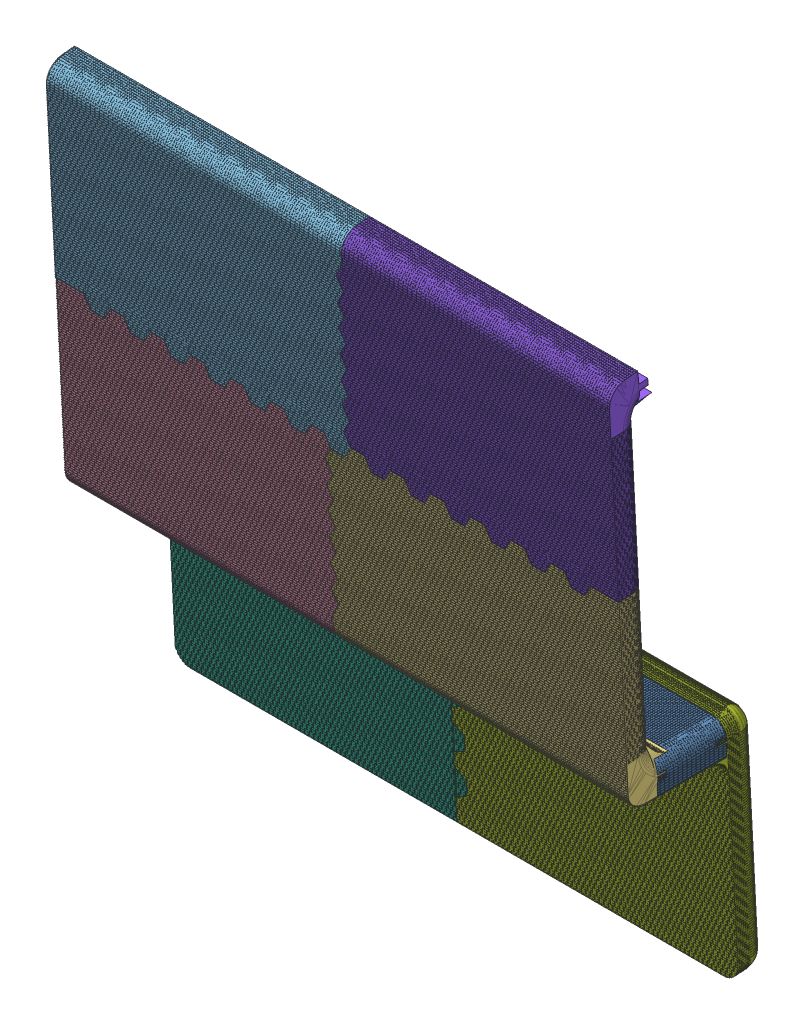
SolidWorks assembly A_B_C_subSplitParts, configuration Default. Lengths in mm.
Overall size (453.06 467.07 127.69).
8 component instances, 8 part files, 14 mates.
Components (placement in the parent):
- B_neo_texture_complete_55mm_1of2-1: B_neo_texture_complete_55mm_1of2 [Default] at (-24.2238 128.3057 314.216) x (1 0 0) z (0 1 0) size (219.85 54.89 24)
- B_neo_texture_complete_55mm_2of2-1: B_neo_texture_complete_55mm_2of2 [Default] at (-24.2238 128.3057 314.216) x (1 0 0) z (0 1 0) size (236.08 54.89 24)
- C_assy_half_hexCut_1of4-1: C_assy_half_hexCut_1of4 [Default] at (189.9657 195.3033 328.4127) x (0 0.99863 0.052336) z (1 0 0) size (151.85 36.3 237.2)
- C_assy_half_hexCut_2of4-1: C_assy_half_hexCut_2of4 [Default] at (189.9657 195.3033 328.4127) x (0 0.99863 0.052336) z (1 0 0) size (151.85 37.29 220.92)
- C_assy_half_hexCut_3of4_Completed-1: C_assy_half_hexCut_3of4_Completed [Default] at (35.1569 242.0747 353.6128) x (0 -0.99863 -0.052336) z (-1 0 0) size (161.09 36.3 237.2)
- A_neo_part1-1: A_neo_part1 [Default] at (190.2996 258.8119 374.6631) x (0 0.99863 0.052336) z (0 0.052336 -0.99863) size (187.3 234.72 36.32)
- A_neo_part2-1: A_neo_part2 [Default] at (190.2996 258.8119 374.6631) x (0 0.99863 0.052336) z (0 0.052336 -0.99863) size (187.33 225.47 36.32)
- C_assy_half_hexCut_4of4-1: C_assy_half_hexCut_4of4 [Default] at (35.1569 242.0747 353.6128) x (0 -0.99863 -0.052336) z (-1 0 0) size (161.09 37.29 220.92)
Mates (geometry in assembly coordinates):
- Coincident5: coincident anti-aligned: line of A_neo_part1-1 through (200.9762 -57.2391 249.5811) axis (0 0.052336 -0.99863); line of A_neo_part2-1 through (200.9762 -56.6843 238.9956) axis (0 -0.052336 0.99863)
- Coincident6: coincident anti-aligned: line of A_neo_part1-1 through (200.9762 -39.5382 250.5087) axis (0 -0.99863 -0.052336); line of A_neo_part2-1 through (200.9762 -57.2391 249.5811) axis (0 0.99863 0.052336)
- Coincident7: coincident: point of B_neo_texture_complete_55mm_1of2-1; moEndPointRef_w of A_neo_part2-1
- Distance1: distance = 0.2 mm anti-aligned: plane of B_neo_texture_complete_55mm_1of2-1 through (423.9762 104.7057 314.8485) normal (0 -1 0); plane of A_neo_part2-1 through (-24.0238 104.5057 259.326) normal (0 1 0)
- Coincident9: coincident anti-aligned: line of B_neo_texture_complete_55mm_1of2-1 through (206.3326 105.1057 295.6471) axis (0 0 1); line of B_neo_texture_complete_55mm_2of2-1 through (206.3326 105.1057 314.216) axis (0 0 -1)
- Coincident12: coincident anti-aligned: line of B_neo_texture_complete_55mm_1of2-1 through (206.3326 105.1057 314.216) axis (0 1 0); line of B_neo_texture_complete_55mm_2of2-1 through (206.3326 113.6057 314.216) axis (0 -1 0)
- Coincident13: coincident aligned: line of B_neo_texture_complete_55mm_1of2-1 through (425.7762 105.1057 314.216) axis (0 1 0); line of C_assy_half_hexCut_1of4-1 through (425.7762 105.1057 314.216) axis (0 1 0)
- Coincident14: coincident aligned: plane of B_neo_texture_complete_55mm_1of2-1 through (425.7762 105.1057 259.326) normal (0 -1 0); plane of C_assy_half_hexCut_1of4-1 through (425.7762 105.1057 337.4478) normal (0 -1 0)
- Coincident15: coincident aligned: line of C_assy_half_hexCut_1of4-1 through (195.4476 135.0896 339.0192) axis (-0.5 -0.864839 -0.045324); line of C_assy_half_hexCut_2of4-1 through (195.4476 135.0896 339.0192) axis (-0.5 -0.864839 -0.045324)
- Coincident16: coincident aligned: line of C_assy_half_hexCut_1of4-1 through (190.1071 144.3269 339.5033) axis (0.5 -0.864839 -0.045324); line of C_assy_half_hexCut_2of4-1 through (190.1071 144.3269 339.5033) axis (0.5 -0.864839 -0.045324)
- Coincident17: coincident anti-aligned: line of C_assy_half_hexCut_2of4-1 through (-2.1742 255.1748 345.3126) axis (-1 0 0); line of C_assy_half_hexCut_3of4_Completed-1 through (-24.2238 255.1748 345.3126) axis (1 0 0)
- Coincident18: coincident anti-aligned: line of C_assy_half_hexCut_2of4-1 through (-24.4238 255.6877 335.5261) axis (0 -0.052336 0.99863); line of C_assy_half_hexCut_3of4_Completed-1 through (-24.4238 255.1748 345.3126) axis (0 0.052336 -0.99863)
- Coincident19: coincident aligned: line of C_assy_half_hexCut_3of4_Completed-1 through (211.1977 384.0689 352.0677) axis (0 0.052336 -0.99863); line of C_assy_half_hexCut_4of4-1 through (211.1977 384.0689 352.0677) axis (0 0.052336 -0.99863)
- Coincident20: coincident aligned: line of C_assy_half_hexCut_3of4_Completed-1 through (206.1049 375.3123 350.6074) axis (0.5 0.864839 0.045324); line of C_assy_half_hexCut_4of4-1 through (206.1049 375.3123 350.6074) axis (0.5 0.864839 0.045324)
